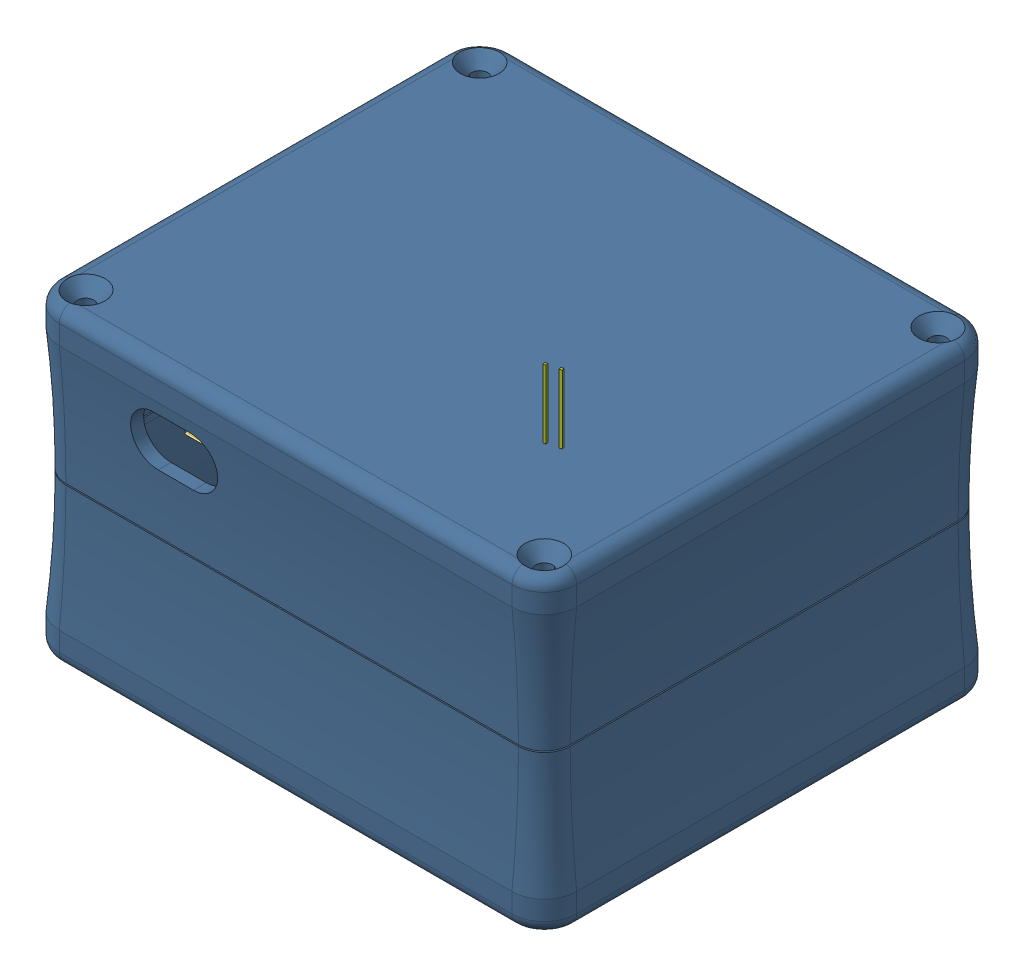
SolidWorks assembly mlab100_1.0, configuration Default. Lengths in mm.
Overall size (101.6 74.5 90.39).
35 component instances, 17 part files, 9 mates.
Components (placement in the parent):
- PCB_Assembly-1: PCB_Assembly [Default] at (68.1296 -90.3917 -65.8118) size (88.9 33.01 84.4)
  - ESP-32-DEV Assembly-1: ESP-32-DEV Assembly [Default] at (-53.7593 43.6972 -6.9189) x (1 0 0) z (0 -1 0) size (26 48.67 13.1)
    - ESP-32-DEV Assembly.stp-1: ESP-32-DEV Assembly.stp [Default] at origin size (26 48.67 13.1)
      - KiCAD-ESP-WROOM-32.stp-1: KiCAD-ESP-WROOM-32.stp [Default] at (-6.9007 2.8189 -1.7678) size (18.07 25.54 3.04)
      - ESP32 PCB.stp-1: ESP32 PCB.stp [Default] at (2.0993 15.5689 -1.7678) x (-1 0 0) z (0 0 -1) size (26 48.2 1.56)
      - molex_0473460001.stp-1: molex_0473460001.stp [Default] at (-6.9007 36.1189 -1.9746) x (-1 0 0) z (0 1 0) size (7.98 2.76 5.43)
      - button.stp-1: button.stp [Default] at (-13.6402 35.5955 -1.7678) x (0 -1 0) z (-1 0 0) size (4 2.2 3)
      - button.stp-2: button.stp [Default] at (-0.0817 35.5955 -1.7678) x (0 -1 0) z (-1 0 0) size (4 2.2 3)
      - AMS1117.stp-1: AMS1117.stp [Default] at (-10.4007 20.5177 -1.1678) x (0 1 0) z (1 0 0) size (6.51 1.86 7)
      - HEADER10P.stp-1: HEADER10P.stp [Default] at (-18.2566 -8.7047 -3.3278) x (-1 0 0) z (0 0 -1) size (2.5 25.4 11.5)
      - HEADER10P.stp-2: HEADER10P.stp [Default] at (-18.2566 14.1553 -3.3278) x (-1 0 0) z (0 0 -1) size (2.5 25.4 11.5)
      - HEADER10P.stp-3: HEADER10P.stp [Default] at (4.4479 -8.6926 -3.3278) x (-1 0 0) z (0 0 -1) size (2.5 25.4 11.5)
      - HEADER10P.stp-4: HEADER10P.stp [Default] at (4.4479 14.1674 -3.3278) x (-1 0 0) z (0 0 -1) size (2.5 25.4 11.5)
  - LED 5mm UV 405nm-1: LED 5mm UV 405nm [Default] at (-11 49.525 12.5) x (0.956064 0 -0.293159) z (0 -1 0) size (5.5 6 29.5)
  - LED 5mm UV 405nm-2: LED 5mm UV 405nm [Default] at (-68.55 41.5167 -45.12) x (1 0 0) z (0 0 -1) size (5.5 6 29.5)
  - EJ503B-ND-1: EJ503B-ND [Default] at (-42.6 49.525 -49.93) x (0 0 -1) z (0 -1 0) size (14.62 9.32 15.3)
  - PCB-1: PCB [Default] at (-9.1405 49.525 -36.8131) x (-1 0 0) z (0 1 0) size (88.9 76.2 1.6)
  - LED 5mm UV 405nm-3: LED 5mm UV 405nm [Default] at (-60.85 41.5167 -45.12) x (1 0 0) z (0 0 -1) size (5.5 6 29.5)
  - LED 5mm UV 405nm-4: LED 5mm UV 405nm [Default] at (-53.15 41.5167 -45.12) x (1 0 0) z (0 0 -1) size (5.5 6 29.5)
- Case-2: Case [Default] at (30.0296 -32.2817 -72.5618) size (101.6 61.25 88.97)
- HeatingBlockAssembly-2: HeatingBlockAssembly [Default] at (67.8317 -97.3137 -55.9425) size (35 55.73 48)
  - ThermalSensor_DS18B20-1: ThermalSensor_DS18B20 [Default] at (-24.7021 11.9221 9.1307) x (-0.184941 0 0.98275) z (-0.98275 0 -0.184941) size (6 45 6)
  - HeatingBlock-1: HeatingBlock [Default] at (0.2979 6.9221 -9.8693) x (-1 0 0) z (0 0 -1) size (35 40 25)
  - Heater_40W_12V-1: Heater_40W_12V [Default] at (-24.7021 26.9221 -3.8693) x (0.959957 0 0.280148) z (-0.280148 0 0.959957) size (6 30 6)
  - Vial2-1: Vial2 [Default] at (-10.7021 38.4261 2.6307) x (-0.837169 0 -0.546944) z (-0.546944 0 0.837169) size (13.01 38 13.01)
  - 91075A112_18-8 SS MALE-FEM THRDED HEX STANDOFF-1: 91075A112_18-8 SS MALE-FEM THRDED HEX STANDOFF [91075A112] at (-3.7021 48.5096 -5.8693) x (0 -1 0) z (0.919897 0 0.392159) size (16.4 5.5 4.76)
  - LED 5mm UV 405nm-1: LED 5mm UV 405nm [Default] at (-10.7021 36.9221 -10.8693) x (0.672724 0.739893 0) z (0 0 1) size (5.5 6 29.5)
  - 92949A143_18-8 SS BUTTON-HEAD SOCKET CAP SCREW-1: 92949A143_18-8 SS BUTTON-HEAD SOCKET CAP SCREW [92949A143] at (-3.7021 59.9013 -5.8693) x (1 0 0) z (0 1 0) size (6.65 6.65 6.98)
  - RubberBumper_9540K708-1: RubberBumper_9540K708 [Default] at (-10.7021 46.9221 2.6307) size (14.29 9.53 14.29)
  - 91075A112_18-8 SS MALE-FEM THRDED HEX STANDOFF-2: 91075A112_18-8 SS MALE-FEM THRDED HEX STANDOFF [91075A112] at (-3.7021 48.5096 11.1307) x (0 -1 0) z (-0.919897 0 0.392159) size (16.4 5.5 4.76)
  - 92949A143_18-8 SS BUTTON-HEAD SOCKET CAP SCREW-3: 92949A143_18-8 SS BUTTON-HEAD SOCKET CAP SCREW [92949A143] at (-3.7021 59.9013 11.1307) x (1 0 0) z (0 1 0) size (6.65 6.65 6.98)
  - 91075A112_18-8 SS MALE-FEM THRDED HEX STANDOFF-3: 91075A112_18-8 SS MALE-FEM THRDED HEX STANDOFF [91075A112] at (-30.7021 48.5096 -5.8693) x (0 -1 0) z (0.919897 0 -0.392159) size (16.4 5.5 4.76)
  - 92949A143_18-8 SS BUTTON-HEAD SOCKET CAP SCREW-4: 92949A143_18-8 SS BUTTON-HEAD SOCKET CAP SCREW [92949A143] at (-30.7021 59.9013 -5.8693) x (-1 0 0) z (0 1 0) size (6.65 6.65 6.98)
  - 91075A112_18-8 SS MALE-FEM THRDED HEX STANDOFF-4: 91075A112_18-8 SS MALE-FEM THRDED HEX STANDOFF [91075A112] at (-30.7021 48.5096 11.1307) x (0 -1 0) z (-0.919897 0 -0.392159) size (16.4 5.5 4.76)
  - 92949A143_18-8 SS BUTTON-HEAD SOCKET CAP SCREW-5: 92949A143_18-8 SS BUTTON-HEAD SOCKET CAP SCREW [92949A143] at (-30.7021 59.9013 11.1307) x (-1 0 0) z (0 1 0) size (6.65 6.65 6.98)
Mates (geometry in assembly coordinates):
- Coincident37: coincident: plane of ? through (0 0 0) normal (0 1 0); plane of assembly through (0 0 0) normal (0 1 0)
- Coincident38: coincident: plane of ? through (0 0 0) normal (0 0 -1); plane of assembly through (0 0 0) normal (0 0 1)
- Coincident39: coincident: plane of ? through (0 0 0) normal (-1 0 0); plane of assembly through (0 0 0) normal (1 0 0)
- Distance1: distance = 0.635 mm: plane of PCB_Assembly-1/PCB-1 through (58.9891 -39.2667 -102.6249) normal (0 1 0); plane of Case-2 through (69.3996 -38.6317 -105.5818) normal (0 -1 0)
- Concentric1: concentric: cylinder of PCB_Assembly-1/PCB-1 through (69.3996 -39.2667 -105.5818) axis (0 -1 0) radius 1.905; circle of Case-2
- Concentric2: concentric: cylinder of PCB_Assembly-1/PCB-1 through (-9.3404 -39.2667 -105.5818) axis (0 -1 0) radius 1.905; circle of Case-2
- Concentric3: concentric: cylinder of PCB_Assembly-1/PCB-1 through (37.1296 -39.2667 -61.8118) axis (0 -1 0) radius 1.5875; cylinder of HeatingBlockAssembly-2/92949A143_18-8 SS BUTTON-HEAD SOCKET CAP SCREW-4 through (37.1296 -37.4125 -61.8118) axis (0 1 0) radius 3.3274
- Coincident41: coincident: plane of PCB_Assembly-1/PCB-1 through (58.9891 -40.8667 -102.6249) normal (0 -1 0); plane of HeatingBlockAssembly-2/91075A112_18-8 SS MALE-FEM THRDED HEX STANDOFF-3 through (36.0513 -40.8667 -64.3411) normal (0 1 0)
- Concentric4: concentric: cylinder of PCB_Assembly-1/PCB-1 through (64.1296 -39.2667 -44.8118) axis (0 -1 0) radius 1.5875; cylinder of HeatingBlockAssembly-2/92949A143_18-8 SS BUTTON-HEAD SOCKET CAP SCREW-3 through (64.1296 -37.4125 -44.8118) axis (0 1 0) radius 3.3274
